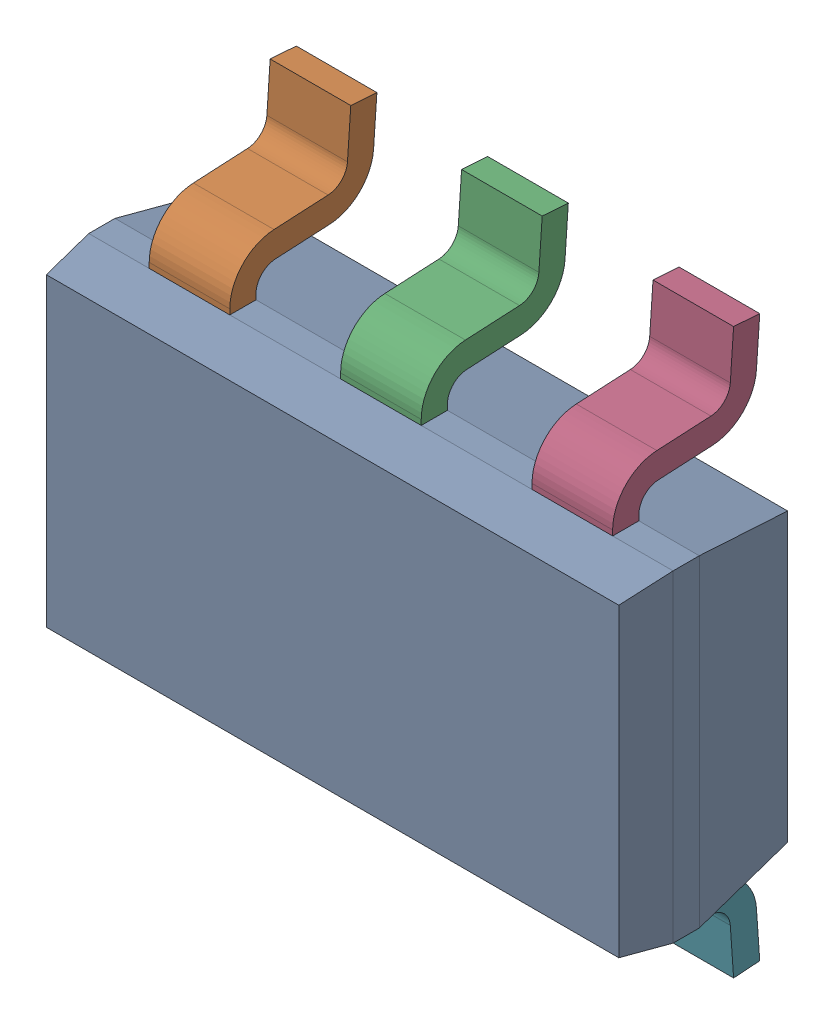
SolidWorks assembly U8, configuration ﾃﾞﾌｫﾙﾄ. Lengths in mm.
Overall size (2.9 2.8 0.97).
8 component instances, 2 part files, 0 mates.
Components (placement in the parent):
- DDC0006A-1: DDC0006A [ﾃﾞﾌｫﾙﾄ] at (33.655 15.875 0) x (0 1 0) z (0 0 1) size (2.8 2.9 0.97)
  - BODY-SOT-1: BODY-SOT [ﾃﾞﾌｫﾙﾄ] at (0 0 0.73) x (0 1 0) z (1 0 0) size (2.9 0.87 1.6)
  - LEAD-SOT-1: LEAD-SOT [ﾃﾞﾌｫﾙﾄ] at (0.9409 0.95 0.25) x (0 1 0) z (1 0 0) size (0.4 0.73 0.6)
  - LEAD-SOT-2: LEAD-SOT [ﾃﾞﾌｫﾙﾄ] at (0.9409 0 0.25) x (0 1 0) z (1 0 0) size (0.4 0.73 0.6)
  - LEAD-SOT-3: LEAD-SOT [ﾃﾞﾌｫﾙﾄ] at (0.9409 -0.95 0.25) x (0 1 0) z (1 0 0) size (0.4 0.73 0.6)
  - LEAD-SOT-4: LEAD-SOT [ﾃﾞﾌｫﾙﾄ] at (-0.9409 0.95 0.25) x (0 -1 0) z (-1 0 0) size (0.4 0.73 0.6)
  - LEAD-SOT-5: LEAD-SOT [ﾃﾞﾌｫﾙﾄ] at (-0.9409 0 0.25) x (0 -1 0) z (-1 0 0) size (0.4 0.73 0.6)
  - LEAD-SOT-6: LEAD-SOT [ﾃﾞﾌｫﾙﾄ] at (-0.9409 -0.95 0.25) x (0 -1 0) z (-1 0 0) size (0.4 0.73 0.6)
